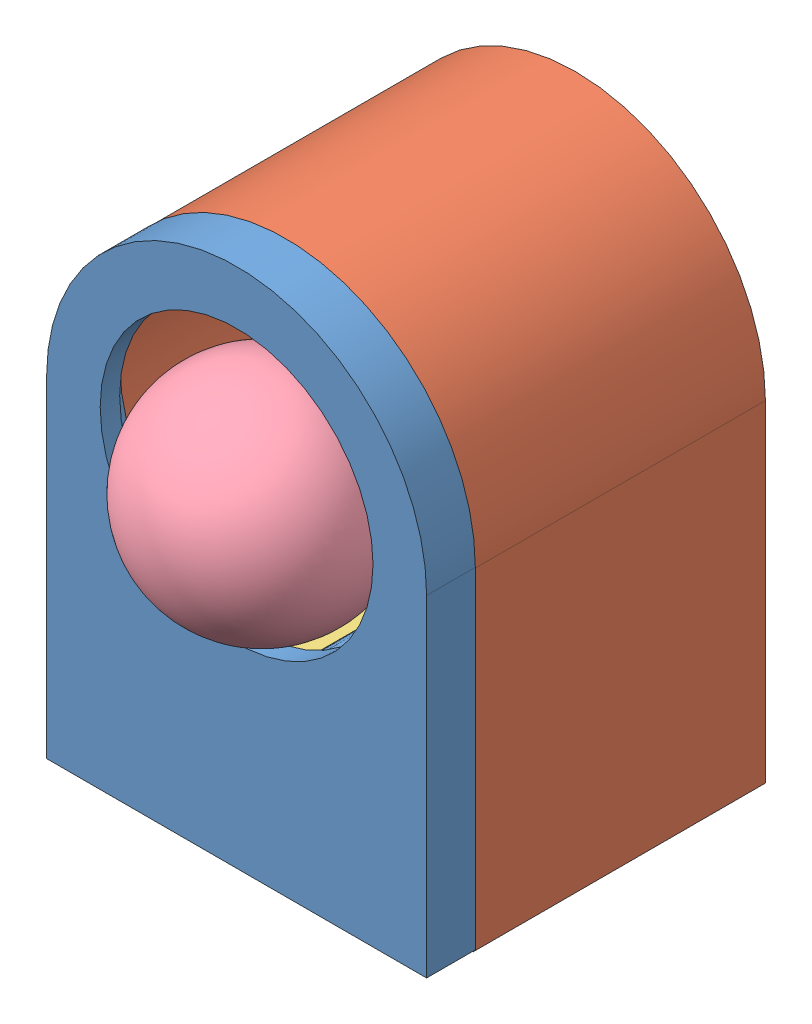
SolidWorks assembly 2, configuration Default. Lengths in mm.
Overall size (104.54 136.15 110).
4 component instances, 4 part files, 1 mates.
Components (placement in the parent):
- Ball Filter 2.2-1: Ball Filter 2.2 [Default] at (36.6078 92.6633 137.4315) size (99.06 135.89 55.88)
- Ball Filter 2.3-1: Ball Filter 2.3 [Default] at (36.5049 92.3998 49.0138) size (99.06 135.89 76.2)
- drawer 2.2-1: drawer 2.2 [Default] at (-13.7498 12.6533 58.0781) x (-0.012671 0 0.99992) z (-0.99992 0 -0.012671) size (66.8 35.05 93.98)
- ball-1: ball [Default] at (36.2139 87.1606 130.4432) size (57.15 57.15 57.15)
Mates (geometry in assembly coordinates):
- Coincident2: coincident: plane of Ball Filter 2.2-1 through (78.0098 12.6533 137.4315) normal (0 1 0); plane of drawer 2.2-1 through (76.413 12.6533 59.2206) normal (0 -1 0)
